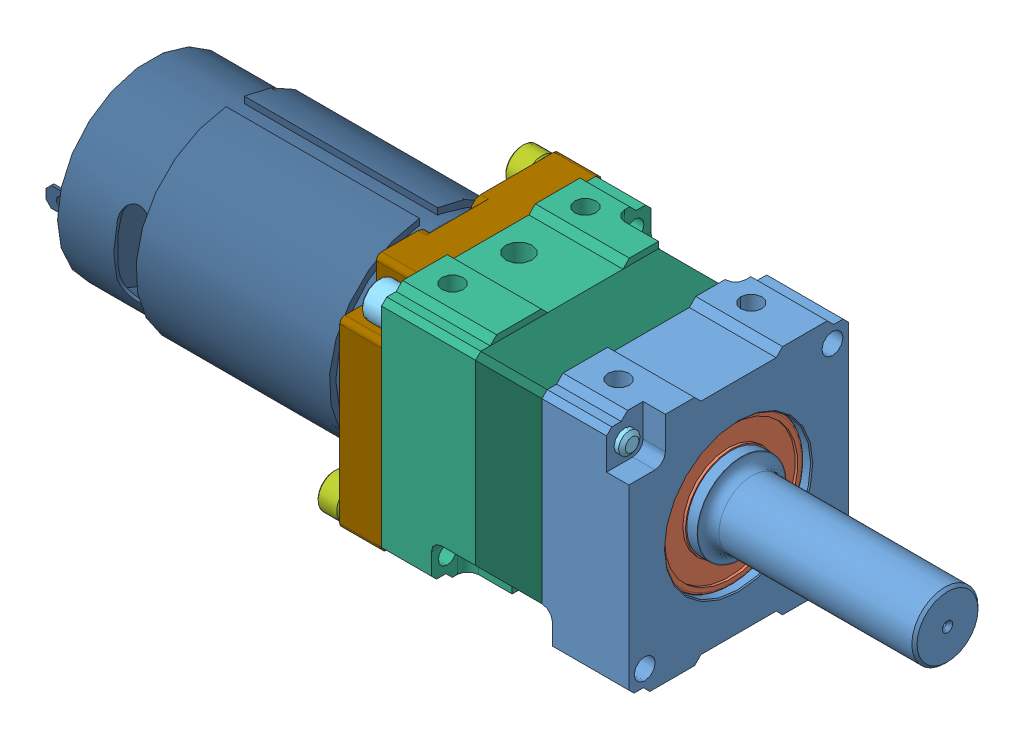
SolidWorks assembly Gearbox Assembly, configuration Default. Lengths in mm.
Overall size (138.95 49.05 49.3).
29 component instances, 19 part files, 2 mates.
Components (placement in the parent):
- 217-2625-026 Rev1-1: 217-2625-026 Rev1 [Default] at (-6.5 22.225 0) x (0 -1 0) z (-1 0 0) size (44.45 42 18.13)
- 217-2742-001 Rev4-1: 217-2742-001 Rev4 [Default] at (0.2002 22.225 0) x (1 0 0) z (0 -0.092627 0.995701) size (7 28 28)
- 217-2742-001 Rev4-2: 217-2742-001 Rev4 [Default] at (8.2002 22.225 0) size (7 28 28)
- 217-2625-017 Rev1_9714K61-1: 217-2625-017 Rev1_9714K61 [Default] at (7.42 22.3002 -0.342) x (0 0.56703 0.823697) z (0 -0.823697 0.56703) size (28.51 4.98 30.18)
- 217-2625-018 Rev1_98541A410-1: 217-2625-018 Rev1_98541A410 [Default] at (-0.7046 22.225 0) x (1 0 0) z (0 -0.017452 0.999848) size (1 19.6 17.4)
- 832-1750-Ring-Gear-Screw_SSA0832-0500ZC-1: 832-1750-Ring-Gear-Screw_SSA0832-0500ZC [Default] at (-30.7 4.725 -17.5) x (0 0.997447 0.071411) z (0 -0.071411 0.997447) size (6.73 48.51 6.73)
- 832-1750-Ring-Gear-Screw_SSA0832-0500ZC-2: 832-1750-Ring-Gear-Screw_SSA0832-0500ZC [Default] at (-30.7 39.725 17.5) x (0 0.005929 0.999982) z (0 -0.999982 0.005929) size (6.73 48.51 6.73)
- 217-2625-025 Rev1-1: 217-2625-025 Rev1 [Default] at (-23.2 22.225 0) x (0 -1 0) z (-1 0 0) size (44.45 42 18)
- 217-4649-002 Rev1_SSA0832-0500ZC-1: 217-4649-002 Rev1_SSA0832-0500ZC [Default] at (-38.7 4.2645 17.9605) x (0 0.33842 -0.940995) z (0 0.940995 0.33842) size (6.73 16.76 6.73)
- 217-4649-002 Rev1_SSA0832-0500ZC-2: 217-4649-002 Rev1_SSA0832-0500ZC [Default] at (-38.7 40.1855 -17.9605) x (0 -0.308932 -0.951084) z (0 0.951084 -0.308932) size (6.73 16.76 6.73)
- 217-4649-005 Rev1_SSA0003-008BA-1: 217-4649-005 Rev1_SSA0003-008BA [Default] at (-36.7 22.225 12.5) x (0 0.5 -0.866025) z (0 -0.866025 -0.5) size (5.5 11 5.5)
- 217-4649-005 Rev1_SSA0003-008BA-2: 217-4649-005 Rev1_SSA0003-008BA [Default] at (-36.7 22.225 -12.5) x (0 -0.5 -0.866025) z (0 -0.866025 0.5) size (5.5 11 5.5)
- 217-2822-004 Rev4-1: 217-2822-004 Rev4 [Default] at (-37.7 22.225 0) x (0 -1 0) z (-1 0 0) size (42 42 9.8)
- FP Motor_AM-9015-1: FP Motor_AM-9015 [Default] at (-67.325 22.225 0) x (0 0 -1) z (1 0 0) size (38 37.92 85.2)
- 217-2820 Rev1_Public-1: 217-2820 Rev1_Public [Default] at (-4.6546 22.225 0) x (0 -0.456494 0.889726) z (-1 0 0) size (39.26 38.9 17.4)
  - 217-2625-100-1: 217-2625-100 [Default] at origin size (39.26 38.9 12.7)
    - 217-2625-008 Rev1-1: 217-2625-008 Rev1 [Default] at origin size (34.7 34.7 4.7)
    - 217-2625-010 Rev1-1: 217-2625-010 Rev1 [Default] at (0 10.193 3.65) x (0.999813 0.019336 0) z (0 0 1) size (4 4 12)
    - 217-2625-010 Rev1-2: 217-2625-010 Rev1 [Default] at (8.691 -5.3258 3.65) size (4 4 12)
    - 217-2625-010 Rev1-3: 217-2625-010 Rev1 [Default] at (-8.691 -5.3258 3.65) size (4 4 12)
    - 217-2625-005 Rev1_Planet_Revolving_Follower01-1: 217-2625-005 Rev1_Planet_Revolving_Follower01 [Default] at (8.691 -5.3258 6.35) x (0.932816 0.360354 0) z (0 0 1) size (16.91 16.92 8)
    - 217-2625-005 Rev1_Planet_Revolving_Follower01-2: 217-2625-005 Rev1_Planet_Revolving_Follower01 [Default] at (-8.691 -5.3258 6.35) x (-0.932788 -0.360426 0) z (0 0 1) size (16.91 16.92 8)
    - 217-2625-005 Rev1_Planet_Revolving_Follower01-3: 217-2625-005 Rev1_Planet_Revolving_Follower01 [Default] at (0 10.193 6.35) x (0.893583 0.448898 0) z (0 0 1) size (16.91 16.92 8)
  - 217-2625-007 Rev1_Public-1: 217-2625-007 Rev1_Public [Default] at (0 0 6.7) x (0.992772 0.120019 0) z (0 0 1) size (14.49 14.49 12.72)
- 217-2816-001 Rev1-1: 217-2816-001 Rev1 [Default] at (-6.35 22.225 0) x (0 -1 0) z (1 0 0) size (42 42 14.5)
- 217-4649-001 Rev1-1: 217-4649-001 Rev1 [Default] at (-20.046 22.225 0) x (0 -1 0) z (1 0 0) size (18 18 13)
- 217-4649-007 Rev1_94105A824-1: 217-4649-007 Rev1_94105A824 [Default] at (-25.521 22.225 -6.7835) x (-0.996104 -0.088191 0) z (0 0 -1) size (4.83 4.83 4.9)
- 217-2625-014 Rev2-1: 217-2625-014 Rev2 [Default] at (-24.7818 22.225 0) x (0 0 1) z (0 -1 0) size (8.01 7.5 7.94)
- Round Output Shaft-2: Round Output Shaft [Default] at (7.4478 22.225 0) x (0 -0.9759 -0.21822) z (1 0 0) size (17 17 44.48)
Mates (geometry in assembly coordinates):
- Concentric4: concentric aligned: cylinder of 217-2742-001 Rev4-1 through (0.2002 22.225 0) axis (-1 0 0) radius 7.5; cylinder of Round Output Shaft-2 through (17.2002 22.225 0) axis (-1 0 0) radius 7.4955
- Coincident1: coincident anti-aligned: plane of 217-2742-001 Rev4-2 through (15.2002 29.725 0) normal (1 0 0); plane of Round Output Shaft-2 through (15.2002 22.225 0) normal (-1 0 0)
